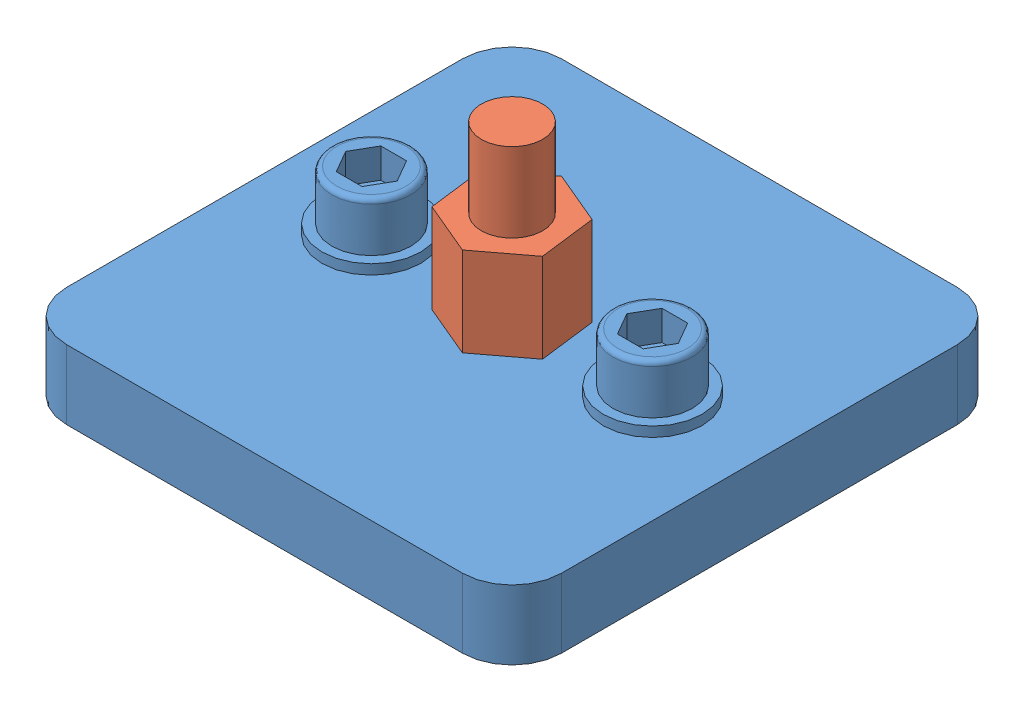
SolidWorks assembly Mini V Gantry Set, configuration Default. Lengths in mm.
Overall size (50 25 50).
2 component instances, 2 part files, 0 mates.
Components (placement in the parent):
- Mini V Gantry Plate-1: Mini V Gantry Plate [Default] at origin size (50 13 50)
- 20.026_L-001-1: 20.026_L-001 [Default] at (0 24 0) x (-0.124096 0 -0.99227) z (0 -1 0) size (11.55 10 25)
